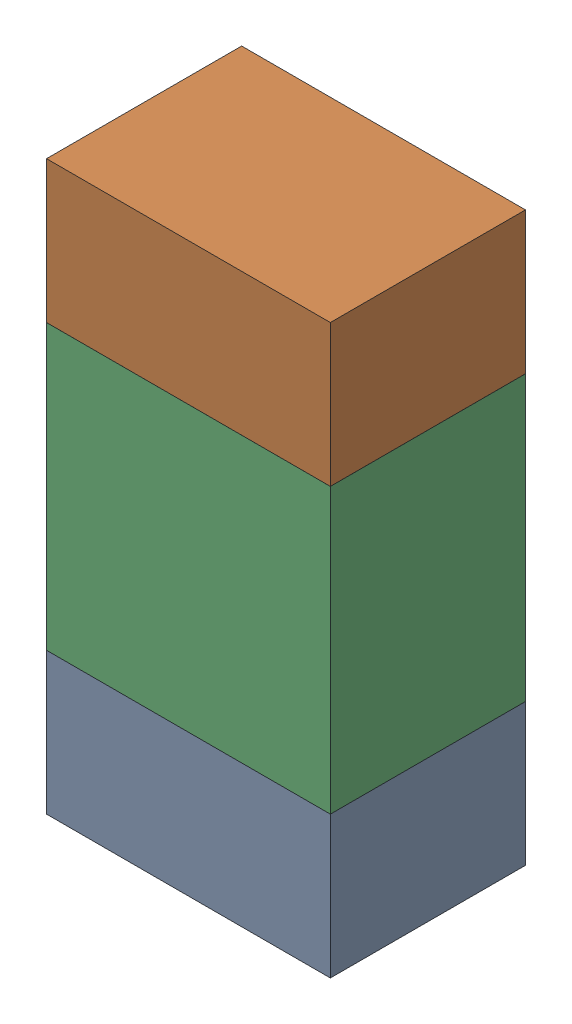
SolidWorks assembly R30, configuration ﾃﾞﾌｫﾙﾄ. Lengths in mm.
Overall size (0.8 1.6 0.55).
6 component instances, 2 part files, 0 mates.
Components (placement in the parent):
- 689261784-1: 689261784 [ﾃﾞﾌｫﾙﾄ] at (20.4999 69.1501 0) size (0.8 0.4 0.55)
  - Extruded_34-1: Extruded_34 [ﾃﾞﾌｫﾙﾄ] at origin size (0.8 0.4 0.55)
- 689261784-2: 689261784 [ﾃﾞﾌｫﾙﾄ] at (20.4999 70.3501 0) size (0.8 0.4 0.55)
  - Extruded_34-1: Extruded_34 [ﾃﾞﾌｫﾙﾄ] at origin size (0.8 0.4 0.55)
- 689261648-1: 689261648 [ﾃﾞﾌｫﾙﾄ] at (20.4999 69.75 0) size (0.8 0.8 0.55)
  - Extruded_33-1: Extruded_33 [ﾃﾞﾌｫﾙﾄ] at origin size (0.8 0.8 0.55)
